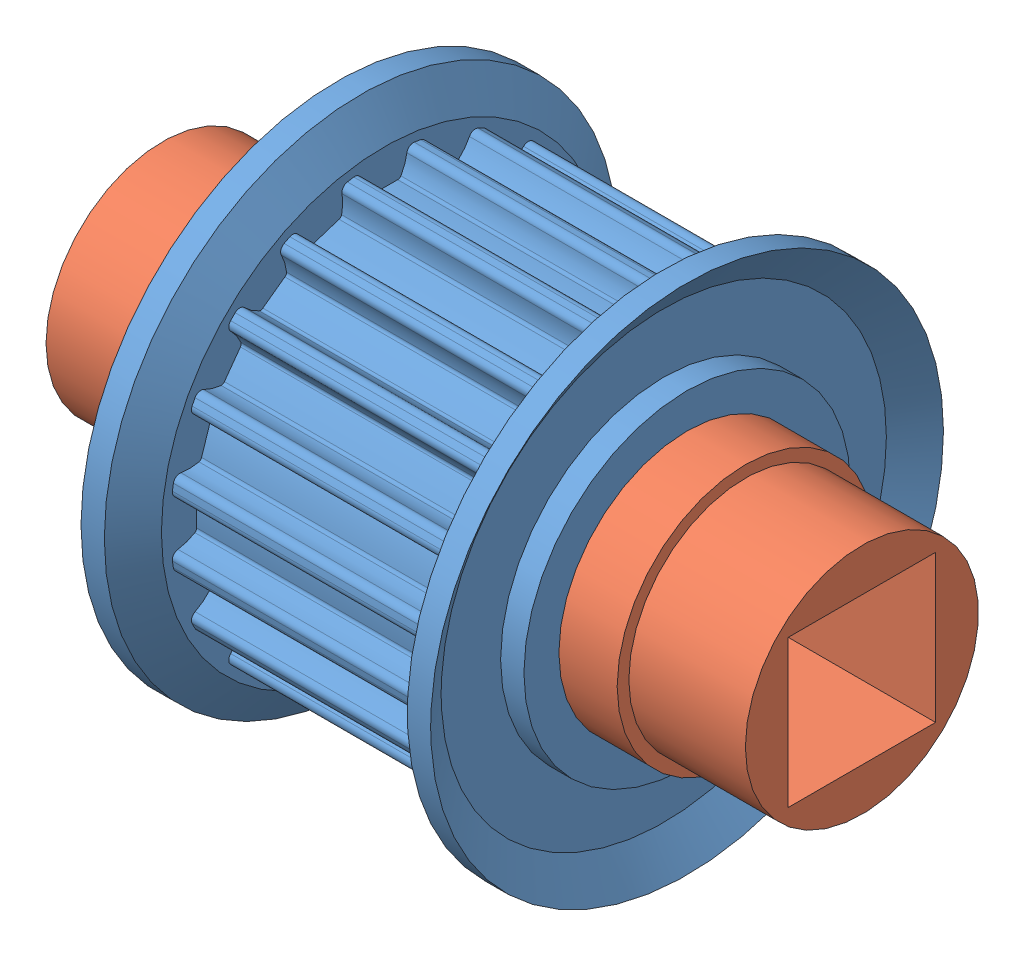
SolidWorks assembly Pulley_MoldedAssm, configuration Default. Lengths in mm.
Overall size (30 22 22).
3 component instances, 3 part files, 9 mates.
Components (placement in the parent):
- AHTF20S3M100flanged_idlers-1: AHTF20S3M100flanged_idlers [Bushing compatible] at origin size (15 22 22)
- Square_Insert^Pulley_MoldedAssm-1: Square_Insert^Pulley_MoldedAssm [Default] at origin size (30 11 11) (virtual)
- Springpin_1-5x4mm_91611A076-1: Springpin_1-5x4mm_91611A076 [Default] at (0 -5.16 0) x (0.459046 0 0.888412) z (0 -1 0) size (1.7 1.65 4.03)
Mates (geometry in assembly coordinates):
- Coincident1: coincident aligned: plane of AHTF20S3M100flanged_idlers-1 through (0 0 0) normal (0 0 1); plane of assembly through (0 0 0) normal (0 0 1)
- Coincident2: coincident aligned: plane of AHTF20S3M100flanged_idlers-1 through (0 0 0) normal (0 1 0); plane of assembly through (0 0 0) normal (0 1 0)
- Coincident3: coincident aligned: plane of AHTF20S3M100flanged_idlers-1 through (0 0 0) normal (1 0 0); plane of assembly through (0 0 0) normal (1 0 0)
- InPlace1: in place: plane of ? through (0 0 0) normal (0 0 1); moOrthogonalPlaneRef_w of ? through (0 0 0) normal (0 1 0); plane of ? through (0 0 0) normal (1 0 0); unknown of ?
- Coincident4: coincident aligned: plane of Square_Insert^Pulley_MoldedAssm-1; plane of assembly
- Coincident5: coincident aligned: plane of ? through (0 0 0) normal (0 1 0)
- Coincident6: coincident anti-aligned: plane of ? through (0 0 0) normal (1 0 0)
- Concentric1: concentric anti-aligned: cylinder of Square_Insert^Pulley_MoldedAssm-1 through (0 -5.5 0) axis (0 1 0) radius 0.75; cylinder of Springpin_1-5x4mm_91611A076-1 through (0 -3.16 0) axis (0 -1 0) radius 0.85
- Coincident4: coincident aligned: plane of Square_Insert^Pulley_MoldedAssm-1 through (-15 -3.16 3.16) normal (0 1 0); plane of Springpin_1-5x4mm_91611A076-1 through (0 -3.16 0) normal (0 1 0)
